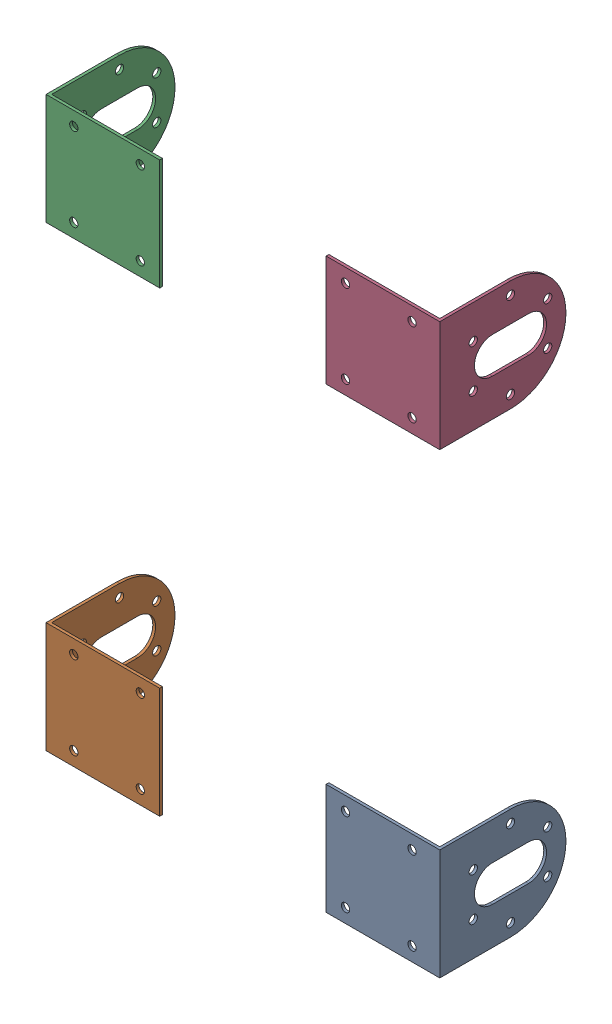
SolidWorks assembly Motor Brackets-1, configuration Varsayılan. Lengths in mm.
Overall size (142 205 45.5).
4 component instances, 4 part files, 0 mates.
Components (placement in the parent):
- Motor Bracket_001-1-1: Motor Bracket_001-1 [Varsayılan] at (71 -115.5 -4) x (-1 0 0) z (0 0 -1) size (41 40 45.5)
- Motor Bracket_002-1-1: Motor Bracket_002-1 [Varsayılan] at (-71 -115.5 -4) x (1 0 0) z (0 0 -1) size (41 40 45.5)
- Motor Bracket_003-1-1: Motor Bracket_003-1 [Varsayılan] at (-71 49.5 -4) x (1 0 0) z (0 0 -1) size (41 40 45.5)
- Motor Bracket_004-1-1: Motor Bracket_004-1 [Varsayılan] at (71 49.5 -4) x (-1 0 0) z (0 0 -1) size (41 40 45.5)
